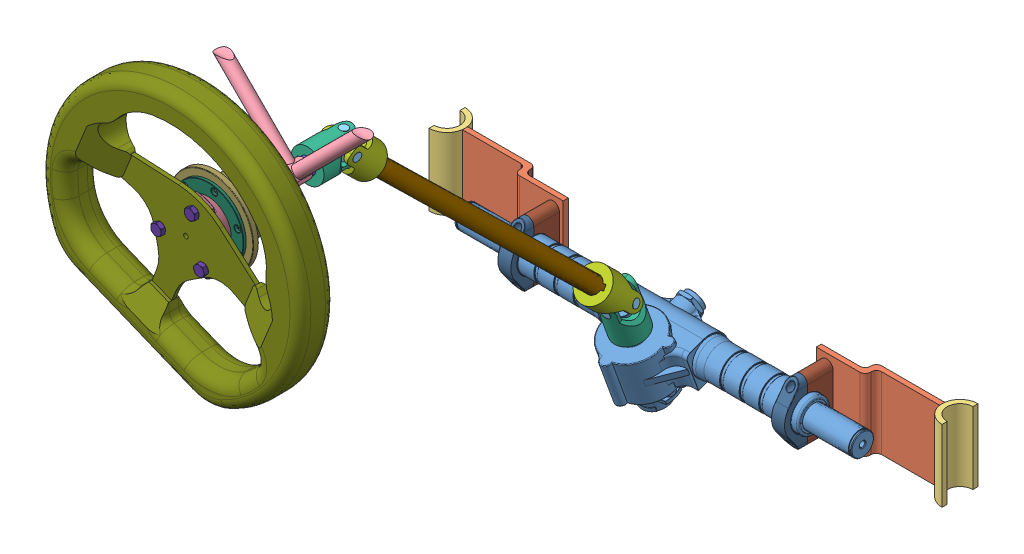
SolidWorks assembly steering attachment, configuration Default. Lengths in mm.
Overall size (500 540.67 538.59).
29 component instances, 17 part files, 65 mates.
Components (placement in the parent):
- steering rack-1: steering rack [Default] at (0 977.0424 1103.2737) x (1 0 0) z (0 0.939693 0.34202) size (386.71 91.44 96.37)
- new rack attachment - 1-1: new rack attachment - 1 [Default] at (171 942.0418 1067.2706) x (0 0 -1) z (1 0 0) size (16 70 109.33)
- new rack attachment - 2-1: new rack attachment - 2 [Default] at (250 942.0418 1064.7706) x (0 0 -1) z (1 0 0) size (35 70 17.5)
- new rack attachment - 1-2: new rack attachment - 1 [Default] at (-171 1012.0424 1067.2706) x (0 0 -1) z (-1 0 0) size (16 70 109.33)
- new rack attachment - 2-2: new rack attachment - 2 [Default] at (-250 942.0424 1064.7706) x (0 0 1) z (-1 0 0) size (35 70 17.5)
- bushing-1: bushing [Default] at (0 1289.6418 1454.7706) size (153.32 78.76 20)
- 23406-116068-1: 23406-116068 [Default] at (0.0598 1028.2232 1150.986) x (-0.08024 0.931824 0.353928) z (-0.170455 0.337015 -0.925941) size (44.48 35.31 32)
  - 23406-116068_02-1: 23406-116068_02 [Default] at (-2.4897 0.1066 2.1372) size (8 32 32)
  - 23406-116068_03-1: 23406-116068_03 [Default] at (-2.4897 0.1066 2.1372) x (0.996679 0.081431 0) z (0 0 1) size (42.01 32 32)
- 23406-116068_01-1: 23406-116068_01 [Default] at (0 1026.6378 1148.1118) x (0 0.699546 0.714587) z (-0.188397 0.701791 -0.68702) size (42.01 32 32)
- steering shaft-1: steering shaft [Default] at (0 1289.6418 1434.7706) size (15.8 15.8 50)
- 23406-116068-2: 23406-116068 [Default] at (0.1296 1287.4863 1414.2979) x (0.081147 -0.006796 -0.996679) z (0.083459 0.996511 0) size (44.48 35.31 32)
  - 23406-116068_02-1: 23406-116068_02 [Default] at (-2.4897 0.1066 2.1372) size (8 32 32)
  - 23406-116068_03-1: 23406-116068_03 [Default] at (-2.4897 0.1066 2.1372) x (0.996679 0.081431 0) z (0 0 1) size (42.01 32 32)
- 23406-116068_01-2: 23406-116068_01 [Default] at (0 1289.6418 1416.7706) x (0 -0.699546 -0.714587) z (-0.116406 -0.709729 0.694791) size (42.01 32 32)
- steering shaft - 2-1: steering shaft - 2 [Default] at (0 1036.4315 1158.1161) x (-0.384321 -0.659707 0.645821) z (0 0.699546 0.714587) size (15.8 15.8 350)
- rack bracket 2-1: rack bracket 2 [Default] at (-133.35 977.0424 1128.2768) x (-1 0 0) z (0 0 -1) size (12.99 60.32 22.25)
- rack bracket 2-2: rack bracket 2 [Default] at (133.35 977.0418 1128.2768) x (-1 0 0) z (0 0 -1) size (12.99 60.32 22.25)
- rack bracket 1-1: rack bracket 1 [Default] at (133.35 977.0418 1103.2737) x (-1 0 0) z (0 0 -1) size (12.7 60.32 25)
- rack bracket 1-2: rack bracket 1 [Default] at (-133.35 977.0424 1103.2737) x (-1 0 0) z (0 0 -1) size (12.7 60.32 25)
- quick release plate attachment1-1: quick release plate attachment1 [Default] at (0 1289.6418 1504.7706) x (0 0 1) z (-0.313393 0.949624 0) size (60.21 82 82)
- F7_QUICK-RELEASE WITH CONNECTOR1-1: F7_QUICK-RELEASE WITH CONNECTOR1 [Default] at (0 1289.6418 1565.4706) x (0 0 -1) z (0.206041 -0.978543 0) size (83.5 76.23 76.23)
  - TE501054mozzoQR210-3d-1: TE501054mozzoQR210-3d [Default] at origin size (55 59 66.73)
  - TE501053pernoQR210-3d-1: TE501053pernoQR210-3d [Default] at (83.5 0 0) x (-1 0 0) z (0 0 -1) size (65 30 30)
  - TE501060boccolaQR200-3d-1: TE501060boccolaQR200-3d [Default] at (17.7 0 0) x (1 0 0) z (0 0.111007 0.99382) size (35 69 69)
- steering wheel-1: steering wheel [Default] at (0 1289.6418 1567.4264) x (0.925949 -0.37765 0) z (0 0 1) size (254 227.58 36.24)
- hex screw gradec_bsi-1: hex screw gradec_bsi [BS EN 24018 - M6 x 12-WN] at (7.8952 1313.7836 1573.7572) x (0 0 -1) z (1 0 0) size (16.38 11.55 10)
- hex screw gradec_bsi-2: hex screw gradec_bsi [BS EN 24018 - M6 x 12-WN] at (16.9598 1270.7335 1573.7572) x (0 0 -1) z (0.931683 0.363273 0) size (16.38 11.55 10)
- hex screw gradec_bsi-3: hex screw gradec_bsi [BS EN 24018 - M6 x 12-WN] at (-24.855 1284.4084 1573.7572) x (0 0 -1) z (1 0 0) size (16.38 11.55 10)
Mates (geometry in assembly coordinates):
- Coincident2: coincident aligned: plane of steering rack-1; plane of assembly through (0 0 0) normal (1 0 0)
- Coincident3: coincident aligned: plane of steering rack-1; plane of assembly through (0 0 0) normal (0 0 1)
- Coincident4: coincident aligned: plane of steering rack-1; plane of assembly through (0 0 0) normal (0 1 0)
- Concentric1: concentric anti-aligned: cylinder of new rack attachment - 1-1 through (250 942.0418 1064.7706) axis (0 1 0) radius 17.5; cylinder of new rack attachment - 2-1 through (250 1012.0418 1064.7706) axis (0 -1 0) radius 17.5
- Coincident5: coincident aligned: plane of new rack attachment - 1-1 through (176 942.0418 1072.2706) normal (0 -1 0); plane of new rack attachment - 2-1 through (250 942.0418 1064.7706) normal (0 -1 0)
- Concentric2: concentric aligned: cylinder of ? through (250 1119.5418 1064.7706) axis (0 -1 0) radius 12.5; cylinder of new rack attachment - 2-1 through (250 1012.0418 1064.7706) axis (0 -1 0) radius 12.5
- Concentric5: concentric aligned: cylinder of new rack attachment - 1-2 through (-250 1012.0424 1064.7706) axis (0 -1 0) radius 17.5; cylinder of new rack attachment - 2-2 through (-250 1012.0424 1064.7706) axis (0 -1 0) radius 17.5
- Coincident8: coincident aligned: plane of new rack attachment - 1-2 through (-176 1012.0424 1072.2706) normal (0 1 0); plane of new rack attachment - 2-2 through (-250 1012.0424 1064.7706) normal (0 1 0)
- Concentric6: concentric aligned: cylinder of ? through (-250 1119.5418 1064.7706) axis (0 -1 0) radius 12.5; cylinder of new rack attachment - 2-2 through (-250 1012.0424 1064.7706) axis (0 -1 0) radius 12.5
- Parallel1: parallel anti-aligned: plane of new rack attachment - 1-2 through (-123.35 942.0424 1078.2706) normal (1 0 0); plane of new rack attachment - 2-2 through (-250 1012.0424 1077.2706) normal (-1 0 0)
- Concentric8: concentric aligned: cylinder of ? through (-200 1369.5418 1464.7706) axis (1 0 0) radius 12.5; cylinder of bushing-1 through (-81.3173 1369.5418 1464.7706) axis (1 0 0) radius 12.5
- Concentric9: concentric aligned: cylinder of ? through (-200 1369.5418 1464.7706) axis (1 0 0) radius 12.5; cylinder of bushing-1 through (-81.3173 1369.5418 1464.7706) axis (1 0 0) radius 12.5
- Concentric10: concentric aligned: cylinder of steering rack-1 through (0 989.3179 1134.5285) axis (0 0.939693 0.34202) radius 7.9375; cylinder of 23406-116068-1/23406-116068_03-1 through (0 994.6883 1136.4832) axis (0 0.939693 0.34202) radius 8
- Coincident13: coincident anti-aligned: plane of steering rack-1 through (0 994.6883 1136.4832) normal (0 0.939693 0.34202); plane of 23406-116068-1/23406-116068_03-1 through (7.8829 995.1547 1135.2018) normal (0 -0.939693 -0.34202)
- Parallel2: parallel anti-aligned: plane of steering rack-1; plane of 23406-116068-1/23406-116068_03-1
- Concentric11: concentric anti-aligned: cylinder of 23406-116068-1/23406-116068_02-1 through (0 1026.6378 1148.1118) axis (0.982093 0.134626 -0.131792) radius 4; cylinder of 23406-116068_01-1 through (31.427 1030.9459 1143.8945) axis (-0.982093 -0.134626 0.131792) radius 4
- Width1: width: plane of 23406-116068-1/23406-116068_02-1 through (-15.874 1026.3475 1150.9284) normal (-0.982093 -0.134626 0.131792); plane of 23406-116068-1/23406-116068_02-1 through (15.553 1030.6555 1146.711) normal (0.982093 0.134626 -0.131792); cylinder of 23406-116068_01-1 through (0 1035.7319 1157.4015) axis (0 -0.699546 -0.714587) radius 16
- Concentric12: concentric aligned: cylinder of bushing-1 through (0 1289.6418 1474.7706) axis (0 0 -1) radius 8; cylinder of steering shaft-1 through (0 1289.6418 1484.7706) axis (0 0 -1) radius 7.9
- Distance2: distance = 20 mm aligned: plane of bushing-1 through (0 1289.6418 1454.7706) normal (0 0 -1); plane of steering shaft-1 through (0 1289.6418 1434.7706) normal (0 0 -1)
- Concentric13: concentric aligned: cylinder of steering shaft-1 through (0 1289.6418 1484.7706) axis (0 0 -1) radius 7.9; cylinder of 23406-116068-2/23406-116068_03-1 through (0 1289.6418 1450.7706) axis (0 0 -1) radius 8
- Coincident16: coincident anti-aligned: plane of steering shaft-1 through (0 1289.6418 1434.7706) normal (0 0 -1); plane of 23406-116068-2/23406-116068_03-1 through (0 1289.6418 1434.7706) normal (0 0 1)
- Parallel3: parallel: plane of 23406-116068-2/23406-116068_03-1; plane of assembly through (0 0 0) normal (0 1 0)
- Concentric14: concentric aligned: cylinder of 23406-116068-2/23406-116068_02-1 through (0 1289.6418 1416.7706) axis (-0.993202 0.083182 -0.081431) radius 4; cylinder of 23406-116068_01-2 through (31.7825 1286.98 1419.3764) axis (-0.993202 0.083182 -0.081431) radius 4
- Width2: width: plane of 23406-116068-2/23406-116068_02-1 through (-15.7289 1290.9592 1413.4744) normal (-0.993202 0.083182 -0.081431); plane of 23406-116068-2/23406-116068_02-1 through (16.0535 1288.2973 1416.0802) normal (0.993202 -0.083182 0.081431); cylinder of 23406-116068_01-2 through (0 1280.5477 1407.481) axis (0 0.699546 0.714587) radius 16
- Concentric15: concentric aligned: cylinder of 23406-116068_01-2 through (0 1289.6418 1416.7706) axis (0 -0.699546 -0.714587) radius 8; cylinder of steering shaft - 2-1 through (0 1281.2727 1408.2216) axis (0 -0.699546 -0.714587) radius 7.9
- Concentric21: concentric anti-aligned: cylinder of 23406-116068_01-1 through (0 1026.6378 1148.1118) axis (0 0.699546 0.714587) radius 8; cylinder of steering shaft - 2-1 through (0 1281.2727 1408.2216) axis (0 -0.699546 -0.714587) radius 7.9
- Parallel9: parallel aligned: plane of steering shaft-1 through (0 1289.6418 1434.7706) normal (0 1 0); plane of assembly through (0 0 0) normal (0 1 0)
- Coincident17: coincident anti-aligned: plane of new rack attachment - 1-2 through (-166 942.0424 1078.2706) normal (0 0 1); plane of rack bracket 1-2 through (-133.35 953.231 1078.2706) normal (0 0 -1)
- Coincident18: coincident aligned: cylinder of new rack attachment - 1-2 through (-133.35 1000.8549 1143.2706) axis (0 0 -1) radius 3.2639; circle of rack bracket 1-2
- Parallel11: parallel aligned: plane of new rack attachment - 1-2 through (-123.35 942.0424 1078.2706) normal (1 0 0); plane of rack bracket 1-2 through (-127 1000.8549 1078.2706) normal (1 0 0)
- Concentric24: concentric aligned: cylinder of rack bracket 2-1 through (-133.35 1000.8549 1103.2737) axis (0 0 1) radius 3.2639; cylinder of rack bracket 1-2 through (-133.35 1000.8549 1078.2706) axis (0 0 1) radius 3.2639
- Concentric25: concentric aligned: cylinder of rack bracket 2-1 through (-133.35 953.231 1103.2737) axis (0 0 1) radius 3.2639; cylinder of rack bracket 1-2 through (-133.35 953.231 1078.2706) axis (0 0 1) radius 3.2639
- Concentric26: concentric aligned: cylinder of steering rack-1 through (-114.6969 977.0424 1103.2737) axis (-1 0 0) radius 16.1036; cylinder of rack bracket 2-1 through (-127 977.0429 1103.2737) axis (-1 0 0) radius 15.875
- Coincident21: coincident anti-aligned: plane of new rack attachment - 1-1 through (166 1012.0418 1078.2706) normal (0 0 1); plane of rack bracket 1-1 through (133.35 953.2304 1078.2706) normal (0 0 -1)
- Concentric27: concentric anti-aligned: cylinder of new rack attachment - 1-1 through (133.35 1000.8543 1143.2706) axis (0 0 -1) radius 3.2639; cylinder of rack bracket 1-1 through (133.35 1000.8543 1078.2706) axis (0 0 1) radius 3.2639
- Parallel12: parallel aligned: plane of new rack attachment - 1-1 through (123.35 1012.0418 1078.2706) normal (-1 0 0); plane of rack bracket 1-1 through (127 1000.8543 1078.2706) normal (-1 0 0)
- Concentric28: concentric aligned: cylinder of rack bracket 2-2 through (133.35 1000.8543 1103.2737) axis (0 0 1) radius 3.2639; cylinder of rack bracket 1-1 through (133.35 1000.8543 1078.2706) axis (0 0 1) radius 3.2639
- Concentric29: concentric aligned: cylinder of rack bracket 2-2 through (133.35 953.2304 1103.2737) axis (0 0 1) radius 3.2639; cylinder of rack bracket 1-1 through (133.35 953.2304 1078.2706) axis (0 0 1) radius 3.2639
- Concentric30: concentric anti-aligned: cylinder of steering rack-1 through (114.6969 977.0424 1103.2737) axis (1 0 0) radius 16.1036; cylinder of rack bracket 2-2 through (139.7 977.0424 1103.2737) axis (-1 0 0) radius 15.875
- Angle1: planar angle = 0.349066 rad aligned: plane of steering rack-1 through (-32.8534 990.1416 1132.2655) normal (0 0.939693 0.34202); plane of rack bracket 2-1
- Concentric31: concentric aligned: cylinder of steering rack-1 through (-114.6969 977.0424 1103.2737) axis (-1 0 0) radius 16.1036; cylinder of rack bracket 1-2 through (-127 977.0424 1103.2737) axis (-1 0 0) radius 15.875
- Coincident25: coincident aligned: plane of steering rack-1 through (-139.7 977.1206 1103.0589) normal (-1 0 0); plane of rack bracket 1-2 through (-139.7 1000.8549 1078.2706) normal (-1 0 0)
- Distance5: distance = 15 mm: plane of ? through (-250 803.984 684.1259) normal (0 1 0); plane of steering rack-1
- Coincident29: coincident aligned: plane of steering rack-1; plane of steering shaft-1 through (0 1289.6418 1434.7706) normal (1 0 0)
- Parallel17: parallel aligned: plane of ? through (-250 907.0418 1464.7706) normal (0 1 0); plane of steering shaft-1 through (0 1289.6418 1434.7706) normal (0 1 0)
- Concentric32: concentric anti-aligned: cylinder of 23406-116068_01-1 through (0 1026.6378 1148.1118) axis (0 0.699546 0.714587) radius 8; cylinder of 23406-116068_01-2 through (0 1289.6418 1416.7706) axis (0 -0.699546 -0.714587) radius 8
- Distance6: distance = 35 mm anti-aligned: plane of new rack attachment - 2-1 through (250 942.0418 1064.7706) normal (0 -1 0); plane of ? through (-250 907.0418 1464.7706) normal (0 1 0)
- Tangent1: tangent anti-aligned: cylinder of 23406-116068_01-1 through (-6.0287 1050.6062 1127.6707) axis (0.188397 -0.701791 0.68702) radius 11.84; plane of steering shaft - 2-1 through (0 1036.4315 1158.1161) normal (0 -0.699546 -0.714587)
- Coincident34: coincident anti-aligned: plane of steering shaft-1 through (0 1289.6418 1484.7706) normal (0 0 1); plane of quick release plate attachment1-1 through (0 1289.6418 1484.7706) normal (0 0 -1)
- Concentric33: concentric anti-aligned: cylinder of steering shaft-1 through (0 1289.6418 1484.7706) axis (0 0 -1) radius 7.9; cylinder of quick release plate attachment1-1 through (0 1289.6418 1484.7706) axis (0 0 1) radius 7.9
- Coincident40: coincident anti-aligned: plane of steering wheel-1 through (0 1289.6418 1569.3822) normal (0 0 1); plane of hex screw gradec_bsi-1 through (7.8952 1319.5571 1569.3822) normal (0 0 -1)
- Concentric56: concentric: cylinder of steering wheel-1 through (-18.9344 1159.044 1402.724) axis (0 0 -1) radius 3.05; cylinder of hex screw gradec_bsi-2 through (24.1296 1150.0456 1401.0106) axis (0 0 1) radius 3
- Coincident41: coincident anti-aligned: plane of steering wheel-1 through (0 1289.6418 1569.3822) normal (0 0 1); plane of hex screw gradec_bsi-2 through (14.8624 1276.1126 1569.3822) normal (0 0 -1)
- Concentric57: concentric: cylinder of steering wheel-1 through (-5.1952 1117.2503 1402.724) axis (0 0 -1) radius 3.05; cylinder of hex screw gradec_bsi-3 through (-8.8414 1118.3017 1401.0106) axis (0 0 1) radius 3
- Coincident42: coincident anti-aligned: plane of steering wheel-1 through (0 1289.6418 1569.3822) normal (0 0 1); plane of hex screw gradec_bsi-3 through (-24.855 1290.1819 1569.3822) normal (0 0 -1)
- Parallel30: parallel anti-aligned: cylinder of steering wheel-1 through (7.8952 1313.7836 1575.4706) axis (0 0 -1) radius 3.05; cylinder of hex screw gradec_bsi-2 through (16.9598 1270.7335 1573.7572) axis (0 0 1) radius 3
- Concentric63: concentric anti-aligned: cylinder of steering wheel-1 through (16.9598 1270.7335 1575.4706) axis (0 0 -1) radius 3.05; cylinder of hex screw gradec_bsi-2 through (16.9598 1270.7335 1573.7572) axis (0 0 1) radius 3
- Concentric64: concentric anti-aligned: cylinder of steering wheel-1 through (-24.855 1284.4084 1575.4706) axis (0 0 -1) radius 3.05; cylinder of hex screw gradec_bsi-3 through (-24.855 1284.4084 1573.7572) axis (0 0 1) radius 3
- Concentric65: concentric anti-aligned: cylinder of steering wheel-1 through (7.8952 1313.7836 1575.4706) axis (0 0 -1) radius 3.05; cylinder of hex screw gradec_bsi-1 through (7.8952 1313.7836 1573.7572) axis (0 0 1) radius 3
- Concentric66: concentric anti-aligned: cylinder of quick release plate attachment1-1 through (0 1289.6418 1509.7706) axis (0 0 1) radius 25; cylinder of F7_QUICK-RELEASE WITH CONNECTOR1-1/TE501060boccolaQR200-3d-1 through (0 1289.6418 1525.0206) axis (0 0 -1) radius 24
- Coincident43: coincident anti-aligned: plane of quick release plate attachment1-1 through (0 1289.6418 1544.7706) normal (0 0 1); plane of F7_QUICK-RELEASE WITH CONNECTOR1-1/TE501060boccolaQR200-3d-1 through (28.2513 1298.9653 1544.7706) normal (0 0 -1)
- Concentric67: concentric anti-aligned: cylinder of F7_QUICK-RELEASE WITH CONNECTOR1-1/TE501054mozzoQR210-3d-1 through (7.8952 1313.7836 1564.9706) axis (0 0 -1) radius 2.55; cylinder of hex screw gradec_bsi-1 through (7.8952 1313.7836 1573.7572) axis (0 0 1) radius 3
- Concentric68: concentric anti-aligned: cylinder of F7_QUICK-RELEASE WITH CONNECTOR1-1/TE501054mozzoQR210-3d-1 through (-24.855 1284.4084 1564.9706) axis (0 0 -1) radius 2.55; cylinder of hex screw gradec_bsi-3 through (-24.855 1284.4084 1573.7572) axis (0 0 1) radius 3
- Coincident44: coincident anti-aligned: plane of F7_QUICK-RELEASE WITH CONNECTOR1-1/TE501054mozzoQR210-3d-1 through (16.8799 1293.196 1565.4706) normal (0 0 1); plane of steering wheel-1 through (0 1289.6418 1565.4706) normal (0 0 -1)
- Concentric69: concentric anti-aligned: circle of quick release plate attachment1-1; cylinder of F7_QUICK-RELEASE WITH CONNECTOR1-1/TE501060boccolaQR200-3d-1 through (6.1022 1319.0147 1547.4706) axis (0 0 -1) radius 3
